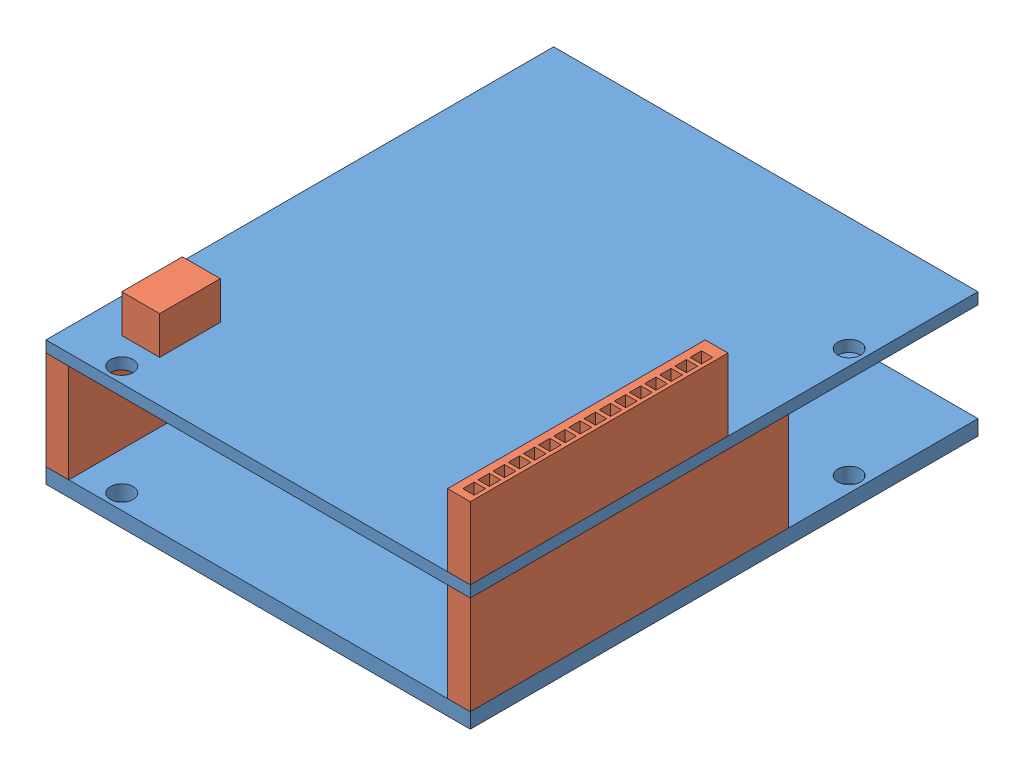
SolidWorks assembly Сборка1, configuration По умолчанию. Lengths in mm.
Overall size (56 26 67).
2 component instances, 2 part files, 4 mates.
Components (placement in the parent):
- RZ-R1-6006-1-1: RZ-R1-6006-1 [По умолчанию] at (36.4143 43.7133 35.9206) size (56 16.5 67)
- Деталь2^Сборка1-1: Деталь2^Сборка1 [По умолчанию] at (36.4143 28.7133 35.9206) x (1 0 0) z (0 1 0) size (56 42 24) (virtual)
Mates (geometry in assembly coordinates):
- На месте1: in place: plane of RZ-R1-6006-1-1 through (36.4143 28.7133 35.9206) normal (0 1 0); plane of Деталь2^Сборка1-1 through (36.4143 28.7133 35.9206) normal (0 1 0); moOrthogonalPlaneRef_w of RZ-R1-6006-1-1 through (36.4143 28.7133 35.9206) normal (0 1 0); plane of Деталь2^Сборка1-1 through (36.4143 28.7133 35.9206) normal (0 0 -1); plane of RZ-R1-6006-1-1 through (36.4143 28.7133 35.9206) normal (0 1 0); unknown of Деталь2^Сборка1-1; plane of RZ-R1-6006-1-1 through (36.4143 28.7133 35.9206) normal (0 1 0); unknown of Деталь2^Сборка1-1
- Совпадение3: coincident aligned: plane of RZ-R1-6006-1-1; plane of ?
- Совпадение4: coincident aligned: moOrthogonalPlaneRef_w of RZ-R1-6006-1-1; plane of Деталь2^Сборка1-1 through (36.4143 28.7133 35.9206) normal (0 0 -1)
- Совпадение5: coincident anti-aligned: moOrthogonalPlaneRef_w of RZ-R1-6006-1-1; plane of Деталь2^Сборка1-1
